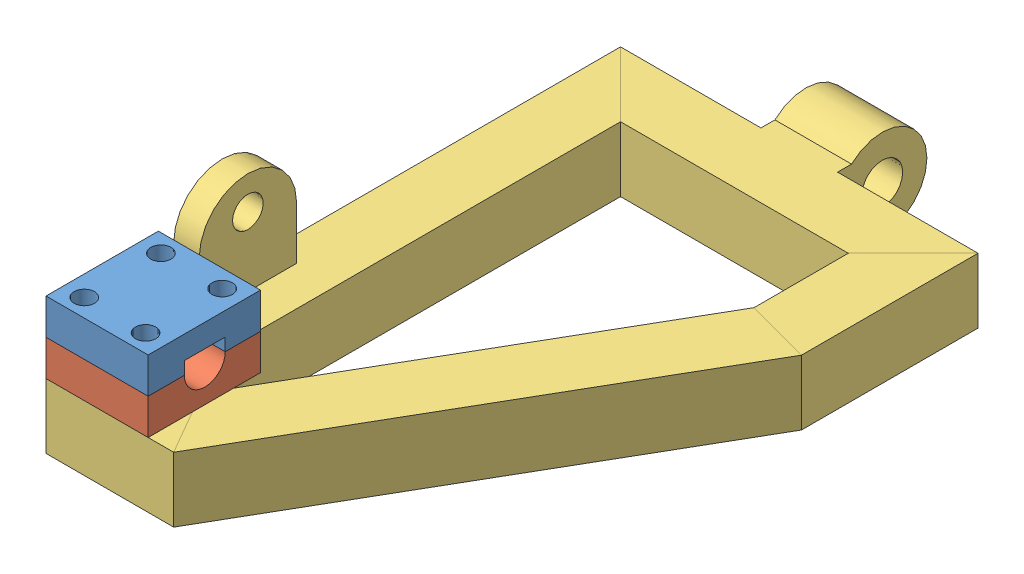
SolidWorks assembly wishbone_assemB, configuration Default. Lengths in mm.
Overall size (140 70.2 255.5).
3 component instances, 3 part files, 6 mates.
Components (placement in the parent):
- motorFitting_1-1: motorFitting_1 [Default] at (22.1624 21.1483 28.9103) x (0 0 -1) z (1 0 0) size (44 14 40)
- motorFitting_2-1: motorFitting_2 [Default] at (22.1624 7.1483 28.9103) x (0 0 -1) z (1 0 0) size (44 14 40)
- wishboneA-1: wishboneA [Default] at (-1.3953 7.1483 51.0993) size (140 70.2 255.5)
Mates (geometry in assembly coordinates):
- Coincident1: coincident aligned: plane of motorFitting_2-1 through (-1.3953 21.1483 51.0993) normal (0 0 1); plane of wishboneA-1 through (48.6047 7.1483 51.0993) normal (0 0 1)
- Coincident2: coincident aligned: plane of motorFitting_2-1 through (-1.3953 21.1483 51.0993) normal (-1 0 0); plane of wishboneA-1 through (-1.3953 7.1483 51.0993) normal (-1 0 0)
- Coincident3: coincident anti-aligned: plane of motorFitting_2-1 through (22.1624 7.1483 28.9103) normal (0 -1 0); plane of wishboneA-1 through (48.6047 7.1483 51.0993) normal (0 1 0)
- Coincident4: coincident aligned: plane of motorFitting_1-1 through (-1.3953 35.1483 51.0993) normal (0 0 1); plane of motorFitting_2-1 through (-1.3953 21.1483 51.0993) normal (0 0 1)
- Coincident5: coincident aligned: plane of motorFitting_1-1 through (-1.3953 35.1483 51.0993) normal (-1 0 0); plane of wishboneA-1 through (-1.3953 7.1483 51.0993) normal (-1 0 0)
- Coincident6: coincident anti-aligned: plane of motorFitting_1-1 through (22.1624 21.1483 28.9103) normal (0 -1 0); plane of motorFitting_2-1 through (22.1624 21.1483 28.9103) normal (0 1 0)
